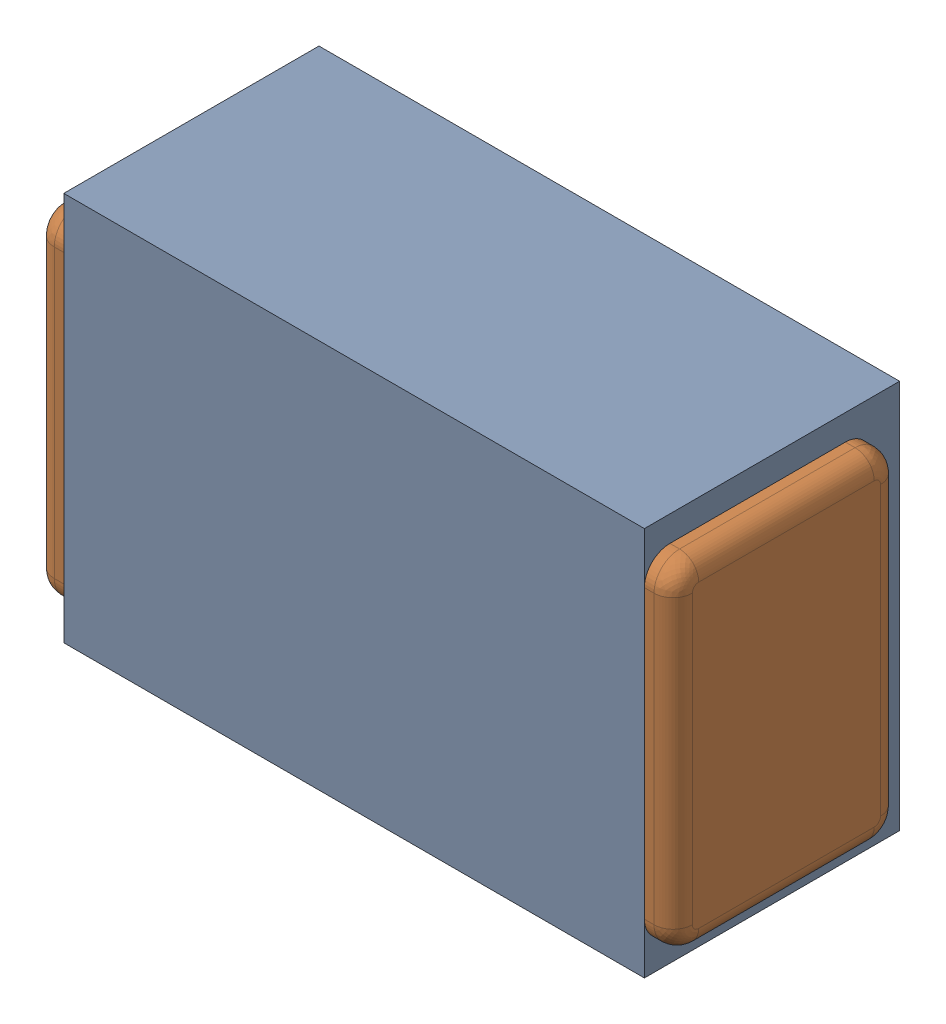
SolidWorks assembly C38, configuration Default. Lengths in mm.
Overall size (1 0.61 0.4).
3 component instances, 2 part files, 0 mates.
Components (placement in the parent):
- 1088880352-1: 1088880352 [Default] at (10.775 23.675 -2.044) size (0.91 0.61 0.4)
  - Extruded-28-1: Extruded-28 [Default] at origin size (0.91 0.61 0.4)
- C0402-1: C0402 [Default] at (10.7751 23.6749 -1.644) x (1 0 0) z (0 1 0) size (1 0.36 0.54)
